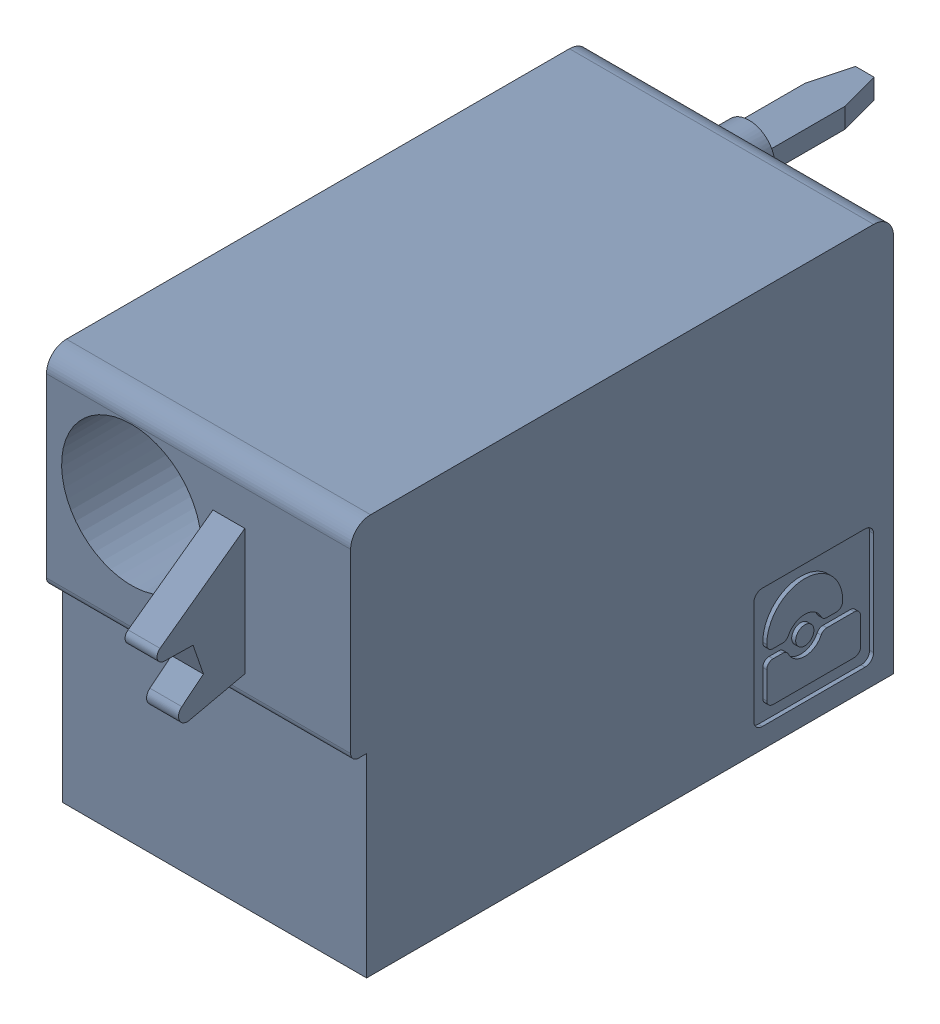
SolidWorks assembly J49, configuration Default. Lengths in mm.
Overall size (7.62 10 19.2).
2 component instances, 1 part files, 0 mates.
Components (placement in the parent):
- 1790487-1: 1790487 [Default] at (129.945 -5.67 -10.6) x (0 1 0) z (1 0 0) size (10 19.2 7.62)
  - ffkdsa1-v2-7.62-1: ffkdsa1-v2-7.62 [Default] at (-15.6914 -27.508 9.12) x (0 -1 0) z (0 0 1) size (19.2 10 7.62)
